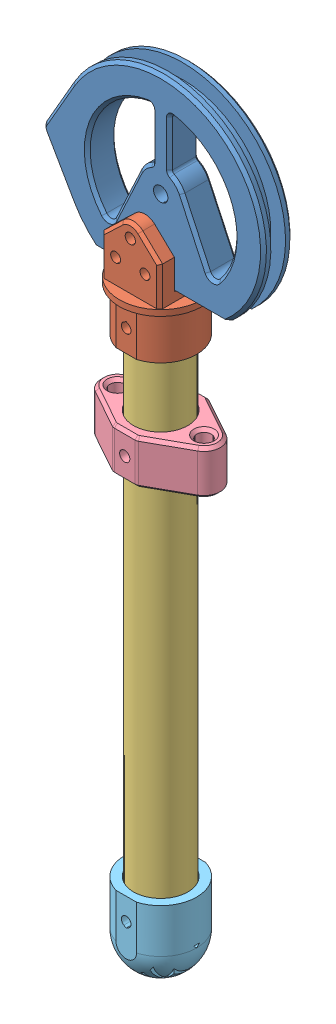
SolidWorks assembly link_foot, configuration ﾃﾞﾌｫﾙﾄ. Lengths in mm.
Overall size (75 268.41 28.1).
5 component instances, 5 part files, 9 mates.
Components (placement in the parent):
- knee_joint_circle-1: knee_joint_circle [ﾃﾞﾌｫﾙﾄ] at origin size (75 60.98 10)
- knee_joint_connector-1: knee_joint_connector [outer] at (-5 -31.1808 5) x (0 0 -1) z (0 1 0) size (28.1 28.1 37.95)
- pipe_foot-1: pipe_foot [ﾃﾞﾌｫﾙﾄ] at (-5 -31.1808 5) x (0 0 1) z (0 -1 0) size (18 18 190)
- wire_end_small-1: wire_end_small [ﾃﾞﾌｫﾙﾄ] at (-5 -76.1808 5) x (1 0 0) z (0 1 0) size (40.5 24.5 15)
- foot_simple-1: foot_simple [ﾃﾞﾌｫﾙﾄ] at (-5 -221.1808 5) x (0 0 -1) z (-1 0 0) size (23.48 27.23 24.5)
Mates (geometry in assembly coordinates):
- 同心円1: concentric anti-aligned: cylinder of knee_joint_circle-1 through (-5 -12.9808 0) axis (0 0 1) radius 1.75; cylinder of knee_joint_connector-1 through (-5 -12.9808 -0.35) axis (0 0 -1) radius 1.75
- 同心円2: concentric anti-aligned: cylinder of knee_joint_circle-1 through (-10 -20.9808 0) axis (0 0 1) radius 1.75; cylinder of knee_joint_connector-1 through (-10 -20.9808 15.35) axis (0 0 -1) radius 1.7
- 幅1: width anti-aligned: plane of knee_joint_connector-1 through (-15 -15.9808 10.35) normal (0 0 -1); plane of knee_joint_circle-1 through (-15 -15.9808 -0.35) normal (0 0 1); plane of knee_joint_connector-1 through (0 0 10) normal (0 0 1); plane of knee_joint_circle-1 through (0 0 0) normal (0 0 -1)
- 同心円5: concentric anti-aligned: cylinder of pipe_foot-1 through (-5 -221.1808 5) axis (0 1 0) radius 9; cylinder of wire_end_small-1 through (-5 -68.6808 5) axis (0 -1 0) radius 9.25
- 同心円6: concentric anti-aligned: cylinder of pipe_foot-1 through (-5 -76.1808 -4) axis (0 0 1) radius 1.75; cylinder of wire_end_small-1 through (-5 -76.1808 17.25) axis (0 0 -1) radius 1.75
- 同心円7: concentric anti-aligned: cylinder of knee_joint_connector-1 through (-5 -38.6808 19.05) axis (0 0 -1) radius 1.65; cylinder of pipe_foot-1 through (-5 -38.6808 -4) axis (0 0 1) radius 1.75
- 同心円8: concentric aligned: cylinder of knee_joint_connector-1 through (-5 -46.1808 5) axis (0 1 0) radius 12.25; cylinder of pipe_foot-1 through (-5 -221.1808 5) axis (0 1 0) radius 9
- 同心円9: concentric anti-aligned: cylinder of pipe_foot-1 through (-5 -213.6808 -4) axis (0 0 1) radius 1.75; cylinder of foot_simple-1 through (-5 -213.6808 16.7394) axis (0 0 -1) radius 1.65
- 同心円10: concentric anti-aligned: cylinder of pipe_foot-1 through (-5 -221.1808 5) axis (0 1 0) radius 9; cylinder of foot_simple-1 through (-5 -206.1808 5) axis (0 -1 0) radius 9.25
